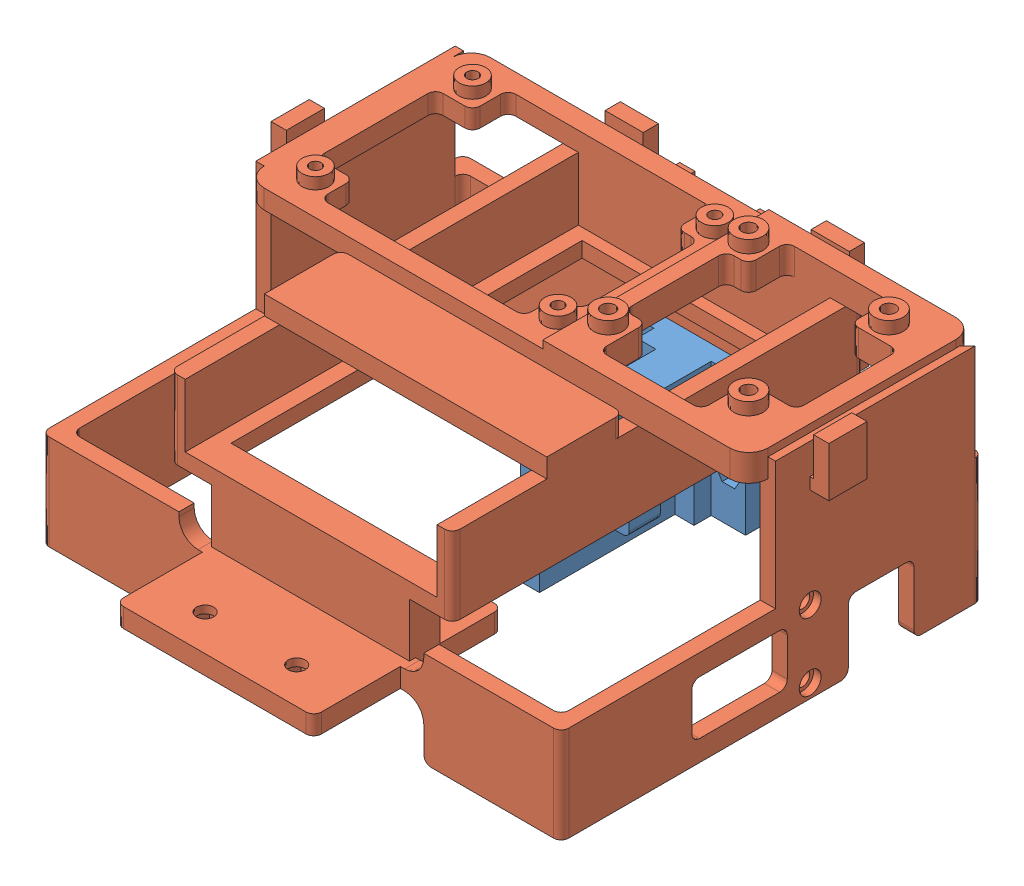
SolidWorks assembly robotFrameAssembly, configuration Default. Lengths in mm.
Overall size (146.16 69.75 147.08).
72 component instances, 33 part files, 10 mates.
Components (placement in the parent):
- Motors, Encoders, Mid Block^robotFrameAssembly-1: Motors, Encoders, Mid Block^robotFrameAssembly [Default] at (-8.998 0 0) size (187.16 56.2 58.85) (virtual)
  - Assem2-1: Assem2 [Default] at (8.998 0 -53.4) x (-1 0 0) z (0 0 1) size (88.58 51.1 58.85) (hidden)
    - Rotary_Encorder_Holder-1: Rotary_Encorder_Holder [Default] at (-68.578 -140.5415 -117.7314) x (0 0 1) z (1 0 0) size (28.42 21.28 29.48) (hidden)
    - Robot Wheel Motor Mount-1: Robot Wheel Motor Mount [Default] at (-28.6 22.5 42) x (0 0 -1) z (1 0 0) size (53.4 22.5 40.1) (hidden)
    - Part1^Assem2-1: Part1^Assem2 [Default] at (-10 22.5 42) x (0 0 -1) z (1 0 0) size (46 51.1 25) (hidden, virtual)
  - Assem2-2: Assem2 [Default] at (156.154 -22.5 -53.4) size (88.58 51.1 58.85) (hidden)
    - Rotary_Encorder_Holder-1: Rotary_Encorder_Holder [Default] at (-68.578 -140.5415 -117.7314) x (0 0 1) z (1 0 0) size (28.42 21.28 29.48) (hidden)
    - Robot Wheel Motor Mount-1: Robot Wheel Motor Mount [Default] at (-28.6 22.5 42) x (0 0 -1) z (1 0 0) size (53.4 22.5 40.1) (hidden)
    - Part1^Assem2-1: Part1^Assem2 [Default] at (-10 22.5 42) x (0 0 -1) z (1 0 0) size (46 51.1 25) (hidden, virtual)
  - t-time-1: t-time [Default] at (87.576 -163.0415 -171.1314) x (0 0 -1) z (-1 0 0) size (44 35 33)
- framePrint2ButForRealsiesHopefuly-2: framePrint2ButForRealsiesHopefuly [Default] at (73.077 -2.4585 -139.1414) x (0 0 1) z (0 1 0) size (147.08 146.16 63.72)
- Caster Wheel d=20mm-1: Caster Wheel d=20mm [Défaut] at (114.7575 -16.025 43.8076) x (0.063898 0 0.997956) z (-0.997956 0 0.063898) size (104.02 31.97 42.2) (hidden)
  - A - Base-1: A - Base [Défaut] at (1.134 3.654 0) size (104.02 8 42.2)
    - Base-1: Base [Défaut] at (-1.008 2.021 37.7647) size (37.76 4 33)
    - Rivet A-1: Rivet A [Défaut] at (-1.008 -0.979 37.7647) size (8.5 5.5 8.5)
    - Rivet B-1: Rivet B [Défaut] at (-1.008 -3.979 37.7647) size (10.5 5 10.5)
  - B - Chape-1: B - Chape [Défaut] at (3.7589 -7.2218 6.9338) x (0.997956 0 0.063898) z (-0.063898 0 0.997956) size (31 19 25)
    - Chape-1: Chape [Défaut] at (11.8446 -6.1032 31) size (31 19 25)
    - Rivet2 A-1: Rivet2 A [Défaut] at (11.8446 -6.1032 22) size (10 10 19.48)
    - Rivet2 B-1: Rivet2 B [Défaut] at (11.8446 -6.1032 40) x (0 0 -1) z (0.975007 0.222176 0) size (14 8 8)
  - C - Galet-1: C - Galet [Défaut] at (13.5984 -13.325 38.6273) x (0.994184 -0.086867 0.063656) z (-0.063898 0 0.997956) size (20 20 14)
  - Part2^Caster Wheel d=20mm-1: Part2^Caster Wheel d=20mm [Default] at (18.2591 -11.5393 38.9257) x (0.063898 0 -0.997956) z (0.932141 0.357143 0.059684) size (0.63 12.78 10) (virtual)
- Assem1-1: Assem1 [Default] at (54.9636 95.8286 13.5462) x (-1 0 0) z (0 -1 0) size (132 108 30.75) (hidden)
  - board-1: board [Default] at (-35.2387 69.1477 66.5921) size (72 49.25 2) (hidden)
  - Part2^Assem1-1: Part2^Assem1 [Default] at (-35.2387 69.1477 66.5921) x (-1 0 0) z (0 0 -1) size (132 108 30.75) (virtual)
  - shield_puente_h_L298N-1: shield_puente_h_L298N [Default] at (-112.6602 45.0457 66.0921) x (-0.004475 0.99999 0) z (0 0 1) size (44.6 44.6 28.1) (hidden)
- HC-SR04.STEP-1: HC-SR04.STEP [Default] at (73.38 12.4865 -70.4014) x (1 0 0) z (0 1 0) size (45.5 21.95 20.5) (hidden)
  - HC-SR04board.STEP-1: HC-SR04board.STEP [Default] at origin size (45.5 1.61 20.5)
  - solder.STEP-1: solder.STEP [Default] at (-3.8014 1.6 8.5727) size (1.17 0.65 1.17)
  - solder.STEP-2: solder.STEP [Default] at (-1.2614 1.6 8.5727) size (1.17 0.65 1.17)
  - solder.STEP-3: solder.STEP [Default] at (1.2786 1.6 8.5727) size (1.17 0.65 1.17)
  - solder.STEP-4: solder.STEP [Default] at (3.8186 1.6 8.5727) size (1.17 0.65 1.17)
  - Emitter.STEP-1: Emitter.STEP [Default] at (-12.75 1.6 0) size (15.9 15.2 15.9)
  - Emitter.STEP-2: Emitter.STEP [Default] at (12.75 1.6 0) size (15.9 15.2 15.9)
  - CrystalOscillator.STEP-1: CrystalOscillator.STEP [Default] at (0 1.6 -7.5) size (13.3 6.4 4.5)
  - solder.STEP-5: solder.STEP [Default] at (-2.0167 0 -7.5286) x (-0.837169 0 -0.546944) z (-0.546944 0 0.837169) size (1.17 0.65 1.17)
  - solder.STEP-6: solder.STEP [Default] at (1.9833 0 -7.5286) x (-0.837169 0 -0.546944) z (-0.546944 0 0.837169) size (1.17 0.65 1.17)
  - smdChip14pin.STEP-1: smdChip14pin.STEP [Default] at (22.25 -0.725 0) x (0 0 -1) z (-1 0 0) size (7.3 1.22 8.75)
  - smdChip14pin.STEP-2: smdChip14pin.STEP [Default] at (4.375 -0.725 0) x (0 0 -1) z (-1 0 0) size (7.3 1.22 8.75)
  - smdChip16pin.STEP-1: smdChip16pin.STEP [Default] at (-18.6 -0.725 5) x (1 0 0) z (0 0 -1) size (7.3 1.22 10)
  - smdceramiccapacitor.STEP-1: smdceramiccapacitor.STEP [Default] at (17.8499 0 -5.5522) x (0 0 -1) z (-1 0 0) size (2.52 0.61 1.3)
  - smdceramiccapacitor.STEP-2: smdceramiccapacitor.STEP [Default] at (17.8499 0 5.585) x (0 0 -1) z (-1 0 0) size (2.52 0.61 1.3)
  - smdceramiccapacitor.STEP-3: smdceramiccapacitor.STEP [Default] at (15.2359 0 8.7006) x (-1 0 0) z (0 0 1) size (2.52 0.61 1.3)
  - smdceramiccapacitor.STEP-4: smdceramiccapacitor.STEP [Default] at (8.3844 0 0.0383) x (-1 0 0) z (0 0 1) size (2.52 0.61 1.3)
  - smdceramiccapacitor.STEP-5: smdceramiccapacitor.STEP [Default] at (8.3844 0 -4.7577) x (-1 0 0) z (0 0 1) size (2.52 0.61 1.3)
  - smdceramiccapacitor.STEP-6: smdceramiccapacitor.STEP [Default] at (8.3844 0 -2.3108) x (-1 0 0) z (0 0 1) size (2.52 0.61 1.3)
  - smdceramiccapacitor.STEP-7: smdceramiccapacitor.STEP [Default] at (-7.8145 0 -2.3108) x (-1 0 0) z (0 0 1) size (2.52 0.61 1.3)
  - smdResistor753.STEP-1: smdResistor753.STEP [Default] at (20.6199 0 5.0565) x (-1 0 0) z (0 0 1) size (2.53 0.63 1.31)
  - smdResistor753.STEP-2: smdResistor753.STEP [Default] at (-7.7732 0 -0.1429) x (-1 0 0) z (0 0 1) size (2.53 0.63 1.31)
  - smdResistor753.STEP-3: smdResistor753.STEP [Default] at (20.6199 0 -4.936) x (-1 0 0) z (0 0 1) size (2.53 0.63 1.31)
  - smdResistor392.STEP-1: smdResistor392.STEP [Default] at (-18.578 0 -6.4389) x (-1 0 0) z (0 0 1) size (2.53 0.63 1.31)
  - smdResistor103.STEP-1: smdResistor103.STEP [Default] at (-18.578 0 6.8031) x (-1 0 0) z (0 0 1) size (2.53 0.63 1.31)
  - smdResistor124.STEP-1: smdResistor124.STEP [Default] at (-7.7732 0 1.8639) x (-1 0 0) z (0 0 1) size (2.53 0.63 1.31)
  - smdResistor103.STEP-2: smdResistor103.STEP [Default] at (-7.7732 0 3.8148) x (-1 0 0) z (0 0 1) size (2.53 0.63 1.31)
  - smdResistor103.STEP-3: smdResistor103.STEP [Default] at (-7.7732 0 5.8773) x (-1 0 0) z (0 0 1) size (2.53 0.63 1.31)
  - smdResistor335.STEP-1: smdResistor335.STEP [Default] at (-7.7732 0 -4.435) x (-1 0 0) z (0 0 1) size (2.53 0.63 1.31)
  - smdResistor102.STEP-1: smdResistor102.STEP [Default] at (8.4383 0 5.8773) x (-1 0 0) z (0 0 1) size (2.53 0.63 1.31)
  - smdResistor103.STEP-4: smdResistor103.STEP [Default] at (8.4383 0 3.8148) x (-1 0 0) z (0 0 1) size (2.53 0.63 1.31)
  - smdResistor563.STEP-1: smdResistor563.STEP [Default] at (8.4383 0 1.8639) x (-1 0 0) z (0 0 1) size (2.53 0.63 1.31)
  - smdResistor103.STEP-5: smdResistor103.STEP [Default] at (8.4383 0 -6.6305) x (-1 0 0) z (0 0 1) size (2.53 0.63 1.31)
  - smdResistor622.STEP-1: smdResistor622.STEP [Default] at (9.6708 0 8.6421) x (-1 0 0) z (0 0 1) size (2.53 0.63 1.31)
  - smdResistor124.STEP-2: smdResistor124.STEP [Default] at (10.2038 0 -8.7291) x (-1 0 0) z (0 0 1) size (2.53 0.63 1.31)
  - smdResistor412.STEP-1: smdResistor412.STEP [Default] at (14.0013 0 -8.7291) x (-1 0 0) z (0 0 1) size (2.53 0.63 1.31)
  - smdResistor103.STEP-6: smdResistor103.STEP [Default] at (17.3324 0 -8.7291) x (-1 0 0) z (0 0 1) size (2.53 0.63 1.31)
  - solder.STEP-7: solder.STEP [Default] at (-12.8084 0 -5.0269) x (-0.837169 0 -0.546944) z (-0.546944 0 0.837169) size (1.17 0.65 1.17)
  - solder.STEP-8: solder.STEP [Default] at (-12.8084 0 5.0295) x (-0.837169 0 -0.546944) z (-0.546944 0 0.837169) size (1.17 0.65 1.17)
  - solder.STEP-9: solder.STEP [Default] at (12.7872 0 5.0295) x (-0.837169 0 -0.546944) z (-0.546944 0 0.837169) size (1.17 0.65 1.17)
  - solder.STEP-10: solder.STEP [Default] at (12.7872 0 -5.0269) x (-0.837169 0 -0.546944) z (-0.546944 0 0.837169) size (1.17 0.65 1.17)
  - headerMale.STEP-1: headerMale.STEP [Default] at (3.81 0 8.58) x (-1 0 0) z (0 0 1) size (2.54 11.1 2.54)
  - headerMale.STEP-2: headerMale.STEP [Default] at (1.27 0 8.58) x (-1 0 0) z (0 0 1) size (2.54 11.1 2.54)
  - headerMale.STEP-3: headerMale.STEP [Default] at (-1.27 0 8.58) x (-1 0 0) z (0 0 1) size (2.54 11.1 2.54)
  - headerMale.STEP-4: headerMale.STEP [Default] at (-3.81 0 8.58) x (-1 0 0) z (0 0 1) size (2.54 11.1 2.54)
Mates (geometry in assembly coordinates):
- Coincident23: coincident aligned: plane of Motors, Encoders, Mid Block^robotFrameAssembly-1/Assem2-1/Robot Wheel Motor Mount-1 through (19.3 -11.25 0) normal (0 0 1)
- Coincident24: coincident anti-aligned: plane of Motors, Encoders, Mid Block^robotFrameAssembly-1/Assem2-1/Robot Wheel Motor Mount-1 through (0 -5 -43.4) normal (-1 0 0)
- Coincident25: coincident aligned: plane of Motors, Encoders, Mid Block^robotFrameAssembly-1/Assem2-1/Robot Wheel Motor Mount-1 through (10 0 -11.4) normal (0 1 0)
- Parallel1: parallel aligned: plane of Motors, Encoders, Mid Block^robotFrameAssembly-1/Part4^Motors, Encoders, Mid Block_robotFrameAssembly-1 through (69.078 5.2365 -51.5514) normal (0 1 0); plane of Caster Wheel d=20mm-1/A - Base-1/Base-1 through (76.1195 -10.35 31.3771) normal (0 1 0)
- Tangent3: tangent aligned: plane of Motors, Encoders, Mid Block^robotFrameAssembly-1/Assem2-2/Part1^Assem2-1 through (167.156 -39.35 -12.85) normal (0 -1 0); torus of Caster Wheel d=20mm-1/C - Galet-1
- Distance1: distance = 8 mm: plane of Motors, Encoders, Mid Block^robotFrameAssembly-1/Part4^Motors, Encoders, Mid Block_robotFrameAssembly-1 through (69.078 5.2365 -11.5514) normal (0 0 1); cylinder of Caster Wheel d=20mm-1/A - Base-1/Base-1 through (73.8831 -11.35 -3.5514) axis (0 1 0) radius 33.5
- Coincident29: coincident anti-aligned: plane of Motors, Encoders, Mid Block^robotFrameAssembly-1/Part4^Motors, Encoders, Mid Block_robotFrameAssembly-1 through (69.078 -163.0415 -171.1314) normal (-1 0 0); plane of Caster Wheel d=20mm-1/Part2^Caster Wheel d=20mm-1 through (69.078 -20.4214 83.1976) normal (1 0 0)
- Lock1: lock: unknown of Motors, Encoders, Mid Block^robotFrameAssembly-1/Assem2-2/Robot Wheel Motor Mount-1; unknown of framePrint2ButForRealsiesHopefuly-2
- Lock2: lock: unknown of framePrint2ButForRealsiesHopefuly-2; unknown of Assem1-1/Part2^Assem1-1
- Coincident37: coincident anti-aligned: plane of Assem1-1/Part2^Assem1-1 through (89.6888 34.7365 -62.0514) normal (0 0 -1); plane of HC-SR04.STEP-1/headerMale.STEP-4 through (69.57 21.0665 -62.0514) normal (0 0 1)
